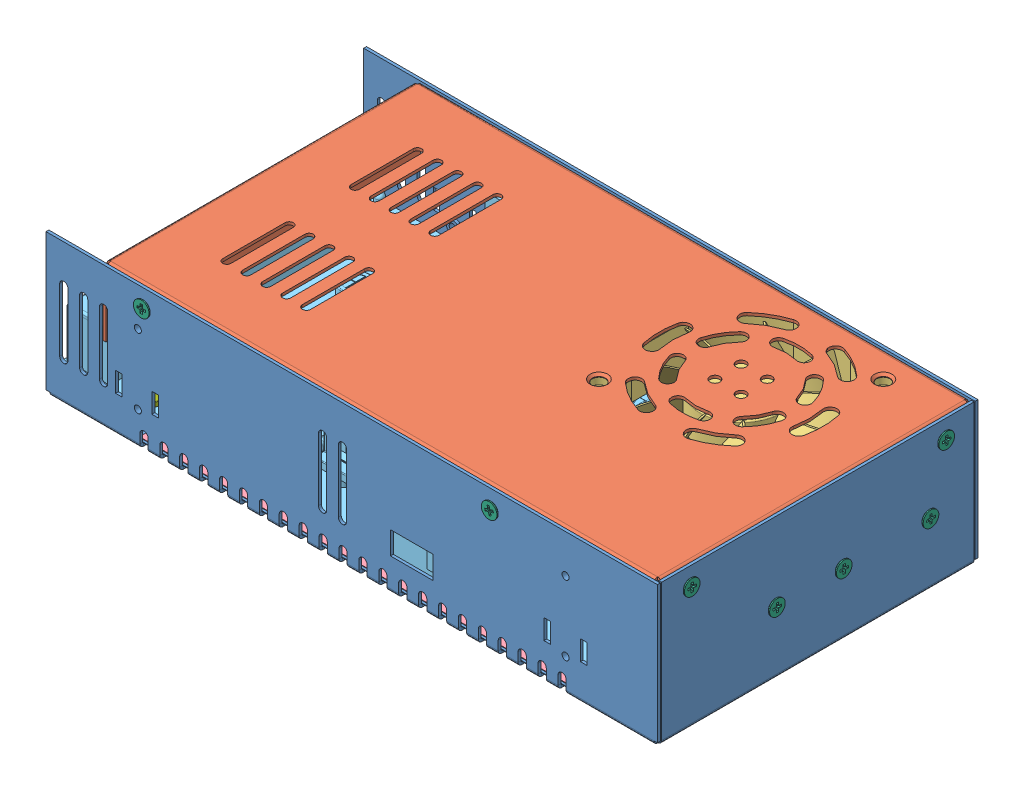
SolidWorks assembly Power supply, configuration Default. Lengths in mm.
Overall size (215.75 49.5 114.2).
22 component instances, 7 part files, 34 mates.
Components (placement in the parent):
- Bottom case-1: Bottom case [Default] at (-52.8079 -21.4842 25.6473) size (215 49.5 112.7)
- Top case-1: Top case [Default] at (-43.8079 27.0158 25.6473) x (-1 0 0) z (0 0 1) size (195 24.2 110.5)
- Cooling_fan-1: Cooling_fan [Default] at (6.8421 19.3658 4.7473) size (60 15.3 60)
- Isulator-1: Isulator [Default] at (-52.8079 -20.4842 25.6473) size (212.4 0.2 110.1)
- PCB-1: PCB [Default] at (-38.0963 -15.5842 28.421) x (-1 0 0) z (0 0 -1) size (210 32.8 108.7)
- countersunk flat head cross recess screw_iso-2: countersunk flat head cross recess screw_iso [ISO 7046-1 - M3 x 4 - Z - 4N] at (-3.7579 21.7158 -31.2277) x (0 0 1) z (-0.999997 -0.00261 0) size (4 5.5 5.5)
- countersunk flat head cross recess screw_iso-3: countersunk flat head cross recess screw_iso [ISO 7046-1 - M3 x 4 - Z - 4N] at (-126.3079 21.7158 -31.4527) x (0 0 1) z (-0.999468 0.032603 0) size (4 5.5 5.5)
- countersunk flat head cross recess screw_iso-5: countersunk flat head cross recess screw_iso [ISO 7046-1 - M3 x 4 - Z - 4N] at (-102.1563 -0.7842 -31.4527) x (0 0 1) z (-0.999426 0.03388 0) size (4 5.5 5.5)
- countersunk flat head cross recess screw_iso-6: countersunk flat head cross recess screw_iso [ISO 7046-1 - M3 x 4 - Z - 4N] at (55.3171 21.7158 70.3973) x (-1 0 0) z (0 -0.007237 -0.999974) size (4 5.5 5.5)
- countersunk flat head cross recess screw_iso-7: countersunk flat head cross recess screw_iso [ISO 7046-1 - M3 x 4 - Z - 4N] at (55.4421 0.7173 40.568) x (-1 0 0) z (0 -0.008634 -0.999963) size (4 5.5 5.5)
- countersunk flat head cross recess screw_iso-8: countersunk flat head cross recess screw_iso [ISO 7046-1 - M3 x 4 - Z - 4N] at (55.4421 0.7169 -13.432) x (-1 0 0) z (0 -0.009276 -0.999957) size (4 5.5 5.5)
- countersunk flat head cross recess screw_iso-9: countersunk flat head cross recess screw_iso [ISO 7046-1 - M3 x 4 - Z - 4N] at (55.3171 21.7158 -19.1027) x (-1 0 0) z (0 0.02196 -0.999759) size (4 5.5 5.5)
- countersunk flat head cross recess screw_iso-10: countersunk flat head cross recess screw_iso [ISO 7046-1 - M3 x 4 - Z - 4N] at (-3.7579 21.7158 82.7473) x (0 0 -1) z (0.96588 0.258989 0) size (4 5.5 5.5)
- countersunk flat head cross recess screw_iso-11: countersunk flat head cross recess screw_iso [ISO 7046-1 - M3 x 4 - Z - 4N] at (-126.3079 21.7158 82.5223) x (0 0 -1) z (1 0 0) size (4 5.5 5.5)
- countersunk flat head cross recess screw_iso-12: countersunk flat head cross recess screw_iso [ISO 7046-1 - M3 x 4 - Z - 4N] at (-47.6563 -0.7842 -31.4527) x (0 0 1) z (-0.999958 -0.009118 0) size (4 5.5 5.5)
- countersunk flat head cross recess screw_iso-13: countersunk flat head cross recess screw_iso [ISO 7046-1 - M3 x 12 - Z - 12N] at (-75.2703 -0.7842 -31.4527) x (0 0 1) z (-0.981775 -0.190045 0) size (12 5.5 5.5)
- countersunk flat head cross recess screw_iso-14: countersunk flat head cross recess screw_iso [ISO 7046-1 - M3 x 12 - Z - 12N] at (55.4421 0.7173 17.0668) x (-1 0 0) z (0 0 -1) size (12 5.5 5.5)
- pan head cross recess screw_iso-2: pan head cross recess screw_iso [ISO 7045 - M3 x 4 - Z - 4N] at (-132.2579 -11.5842 73.2473) x (0 -1 0) z (-0.291898 0 0.956449) size (6.35 5.6 5.6)
- pan head cross recess screw_iso-3: pan head cross recess screw_iso [ISO 7045 - M3 x 4 - Z - 4N] at (-132.2579 -11.5842 -21.9527) x (0 -1 0) z (0 0 1) size (6.35 5.6 5.6)
- pan head cross recess screw_iso-4: pan head cross recess screw_iso [ISO 7045 - M3 x 4 - Z - 4N] at (-43.1079 -11.5842 33.4973) x (0 -1 0) z (-0.76861 0 0.639718) size (6.35 5.6 5.6)
- pan head cross recess screw_iso-5: pan head cross recess screw_iso [ISO 7045 - M3 x 4 - Z - 4N] at (45.2421 -11.5842 -21.9527) x (0 -1 0) z (0 0 1) size (6.35 5.6 5.6)
- pan head cross recess screw_iso-6: pan head cross recess screw_iso [ISO 7045 - M3 x 4 - Z - 4N] at (45.2421 -11.5842 73.2473) x (0 -1 0) z (0 0 1) size (6.35 5.6 5.6)
Mates (geometry in assembly coordinates):
- Width1: width aligned: plane of Top case-1 through (-43.8079 27.0158 80.8973) normal (0 0 1); plane of Top case-1 through (-43.8079 27.0158 -29.6027) normal (0 0 -1); plane of Bottom case-1 through (-52.8079 -21.4842 -29.7027) normal (0 0 1); plane of Bottom case-1 through (-52.8079 -21.4842 80.9973) normal (0 0 -1)
- Coincident1: coincident aligned: plane of Bottom case-1 through (54.6921 28.0158 -30.7027) normal (0 1 0); plane of Top case-1 through (-43.8079 28.0158 25.6473) normal (0 1 0)
- Coincident3: coincident anti-aligned: plane of Bottom case-1 through (53.6921 -21.4842 25.6473) normal (-1 0 0); plane of Top case-1 through (53.6921 27.0158 25.6473) normal (1 0 0)
- Coincident4: coincident anti-aligned: plane of Top case-1 through (-43.8079 27.0158 25.6473) normal (0 -1 0); plane of Cooling_fan-1 through (-17.6579 27.0158 -19.7527) normal (0 1 0)
- Coincident5: coincident aligned: line of Top case-1 through (6.8421 28.0658 4.7473) axis (0 -1 0); line of Cooling_fan-1 through (6.8421 25.0227 4.7473) axis (0 -1 0)
- Width2: width anti-aligned: plane of Isulator-1 through (-159.0079 -19.2842 -29.4027) normal (0 0 -1); plane of Bottom case-1 through (53.3921 -19.2842 80.6973) normal (0 0 1); plane of Isulator-1 through (-52.8079 -21.4842 -29.7027) normal (0 0 1); plane of Bottom case-1 through (-52.8079 -21.4842 80.9973) normal (0 0 -1)
- Concentric3: concentric anti-aligned: cylinder of Bottom case-1 through (45.2421 -15.5842 -21.9527) axis (0 -1 0) radius 2.4; cylinder of Isulator-1 through (45.2421 -20.4842 -21.9527) axis (0 1 0) radius 3.5
- Coincident8: coincident anti-aligned: plane of Bottom case-1 through (23.1921 -19.4842 0.7973) normal (0 1 0); plane of Isulator-1 through (-52.8079 -19.4842 25.6473) normal (0 -1 0)
- Width3: width anti-aligned: plane of PCB-1 through (49.6921 -252.0492 -28.7027) normal (0 0 -1); plane of Bottom case-1 through (49.6921 -252.0492 79.9973) normal (0 0 1); plane of PCB-1 through (-52.8079 -21.4842 -29.7027) normal (0 0 1); plane of Bottom case-1 through (-52.8079 -21.4842 80.9973) normal (0 0 -1)
- Coincident9: coincident aligned: plane of Bottom case-1 through (-160.3079 -21.4842 25.6473) normal (-1 0 0); plane of PCB-1 through (-160.3079 -252.0492 79.9973) normal (-1 0 0)
- Coincident10: coincident anti-aligned: plane of Bottom case-1 through (45.2421 -15.5842 -21.9527) normal (0 1 0); plane of PCB-1 through (-38.0963 -15.5842 28.421) normal (0 -1 0)
- Coincident11: coincident aligned: cone of Top case-1 through (-3.7579 21.7158 -29.6027) axis (0 0 1); cone of countersunk flat head cross recess screw_iso-2 through (-3.7579 21.7158 -30.8277) axis (0 0 1)
- Coincident12: coincident aligned: cone of Bottom case-1 through (-126.3079 21.7158 -30.7027) axis (0 0 1); cone of countersunk flat head cross recess screw_iso-3 through (-126.3079 21.7158 -31.0527) axis (0 0 1)
- Coincident13: coincident aligned: cone of Bottom case-1 through (-102.1563 -0.7842 -29.9027) axis (0 0 1); cone of countersunk flat head cross recess screw_iso-5 through (-102.1563 -0.7842 -31.0527) axis (0 0 1)
- Coincident14: coincident aligned: cone of Top case-1 through (53.6921 21.7158 70.3973) axis (-1 0 0); cone of countersunk flat head cross recess screw_iso-6 through (54.9171 21.7158 70.3973) axis (-1 0 0)
- Coincident15: coincident aligned: cone of Bottom case-1 through (53.8921 0.7173 40.568) axis (-1 0 0); cone of countersunk flat head cross recess screw_iso-7 through (55.0421 0.7173 40.568) axis (-1 0 0)
- Coincident16: coincident aligned: cone of Bottom case-1 through (53.8921 0.7169 -13.432) axis (-1 0 0); cone of countersunk flat head cross recess screw_iso-8 through (55.0421 0.7169 -13.432) axis (-1 0 0)
- Coincident17: coincident aligned: cone of Top case-1 through (53.6921 21.7158 -19.1027) axis (-1 0 0); cone of countersunk flat head cross recess screw_iso-9 through (54.9171 21.7158 -19.1027) axis (-1 0 0)
- Coincident18: coincident aligned: cone of Bottom case-1 through (-3.7579 21.7158 81.9973) axis (0 0 -1); cone of countersunk flat head cross recess screw_iso-10 through (-3.7579 21.7158 82.3473) axis (0 0 -1)
- Coincident191: coincident aligned: cone of Top case-1 through (-126.3079 21.7158 80.8973) axis (0 0 -1); cone of countersunk flat head cross recess screw_iso-11 through (-126.3079 21.7158 82.1223) axis (0 0 -1)
- Coincident20: coincident aligned: cone of Bottom case-1 through (-47.6563 -0.7842 -29.9027) axis (0 0 1); cone of countersunk flat head cross recess screw_iso-12 through (-47.6563 -0.7842 -31.0527) axis (0 0 1)
- Concentric51: concentric anti-aligned: cylinder of Bottom case-1 through (-75.2703 -0.7842 -28.7027) axis (0 0 -1) radius 1.6; cone of countersunk flat head cross recess screw_iso-13 through (-75.2703 -0.7842 -31.0527) axis (0 0 1)
- Coincident211: coincident aligned: cone of Bottom case-1 through (53.8921 0.7173 17.0668) axis (-1 0 0); cone of countersunk flat head cross recess screw_iso-14 through (55.0421 0.7173 17.0668) axis (-1 0 0)
- Coincident22: coincident aligned: cone of Bottom case-1 through (-75.2703 -0.7842 -29.9027) axis (0 0 1); cone of countersunk flat head cross recess screw_iso-13 through (-75.2703 -0.7842 -31.0527) axis (0 0 1)
- Concentric6: concentric aligned: cylinder of Bottom case-1 through (-132.2579 -15.5842 73.2473) axis (0 1 0) radius 1.25; cylinder of pan head cross recess screw_iso-2 through (-132.2579 13.8158 73.2473) axis (0 1 0) radius 2.8
- Concentric7: concentric aligned: cylinder of PCB-1 through (-132.2579 -18.73 -21.9527) axis (0 1 0) radius 1.6; cylinder of pan head cross recess screw_iso-3 through (-132.2579 13.8158 -21.9527) axis (0 1 0) radius 2.8
- Coincident23: coincident anti-aligned: plane of PCB-1 through (-38.0963 -13.9842 28.421) normal (0 1 0); plane of pan head cross recess screw_iso-3 through (-130.7579 -13.9842 -21.9527) normal (0 -1 0)
- Concentric8: concentric anti-aligned: cone of Bottom case-1 through (-43.1079 -15.5842 33.4973) axis (0 -1 0); cylinder of pan head cross recess screw_iso-4 through (-43.1079 13.8158 33.4973) axis (0 1 0) radius 2.8
- Concentric9: concentric aligned: cylinder of PCB-1 through (45.2421 -18.73 -21.9527) axis (0 1 0) radius 1.6; cylinder of pan head cross recess screw_iso-5 through (45.2421 13.8158 -21.9527) axis (0 1 0) radius 2.8
- Coincident25: coincident anti-aligned: plane of PCB-1 through (-38.0963 -13.9842 28.421) normal (0 1 0); plane of pan head cross recess screw_iso-5 through (46.7421 -13.9842 -21.9527) normal (0 -1 0)
- Concentric10: concentric aligned: cylinder of PCB-1 through (45.2421 -18.73 73.2473) axis (0 1 0) radius 1.6; cylinder of pan head cross recess screw_iso-6 through (45.2421 13.8158 73.2473) axis (0 1 0) radius 2.8
- Coincident26: coincident anti-aligned: plane of PCB-1 through (-38.0963 -13.9842 28.421) normal (0 1 0); plane of pan head cross recess screw_iso-6 through (46.7421 -13.9842 73.2473) normal (0 -1 0)
- Coincident27: coincident aligned: plane of PCB-1 through (-38.0963 -13.9842 28.421) normal (0 1 0); circle of pan head cross recess screw_iso-2
- Coincident28: coincident aligned: plane of PCB-1 through (-38.0963 -13.9842 28.421) normal (0 1 0); circle of pan head cross recess screw_iso-4
